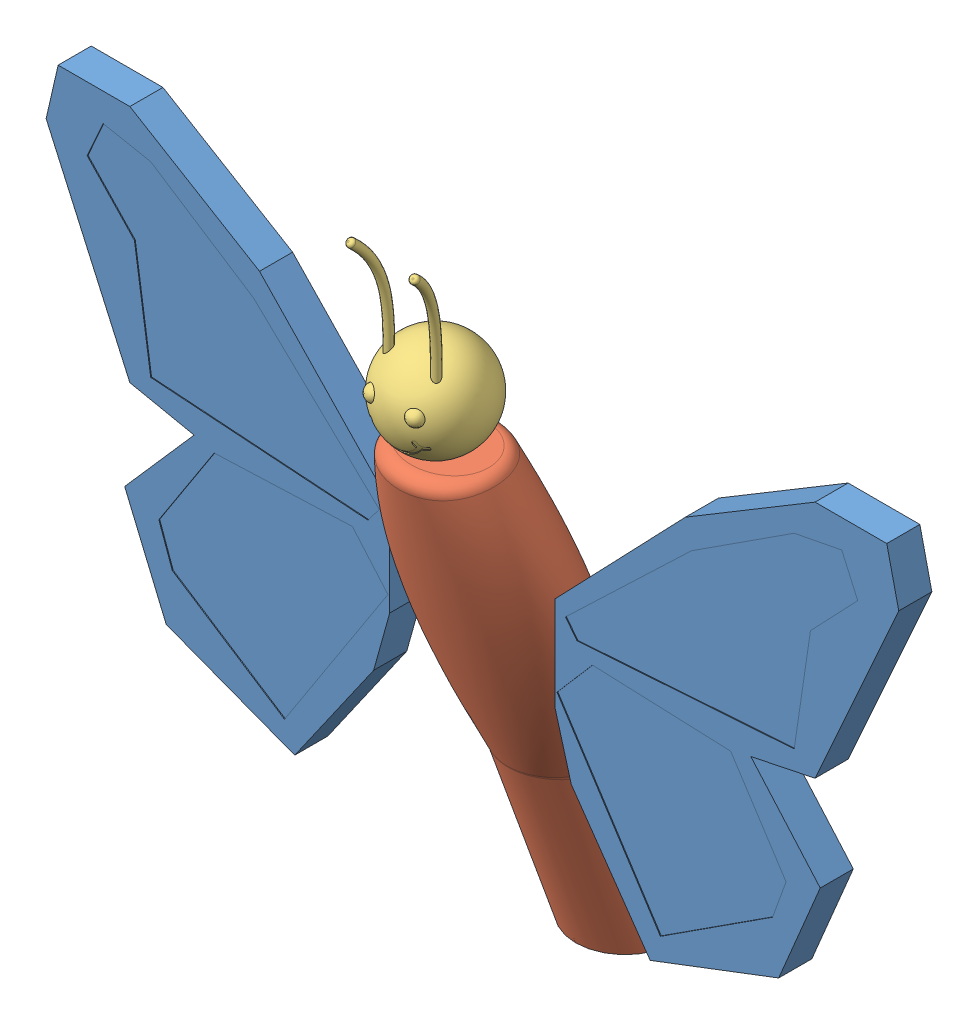
SolidWorks assembly Assem1, configuration Default. Lengths in mm.
Overall size (2617.43 2113.87 901.92).
4 component instances, 3 part files, 6 mates.
Components (placement in the parent):
- Wing-1: Wing [Default] at (371.665 221.4807 1594.4083) size (1207.07 1471.46 101.61)
- Body-1: Body [Default] at (625.7054 -140.7403 1226.9822) size (574.9 1524 859.04)
- Wing-2: Wing [Default] at (879.7459 221.4807 1696.0083) x (-1 0 0) z (0 0 -1) size (1207.07 1471.46 101.61)
- Head-1: Head [Default] at (619.7065 1535.6597 1803.3329) size (304.8 589.87 325.57)
Mates (geometry in assembly coordinates):
- Parallel1: parallel: plane of Wing-1 through (371.665 221.4807 1696.0083) normal (1 0 0); plane of Wing-2 through (879.7459 137.2835 1594.4083) normal (-1 0 0)
- Coincident2: coincident: plane of Wing-1 through (371.665 221.4807 1693.4683) normal (0 0 1); plane of Wing-2 through (879.7459 137.2835 1693.4683) normal (0 0 1)
- Tangent1: tangent: plane of Wing-1 through (371.665 221.4807 1696.0083) normal (1 0 0); face of Body-1
- Tangent2: tangent: face of Body-1; plane of Wing-2 through (879.7459 221.4807 1594.4083) normal (-1 0 0)
- Coincident3: coincident: plane of Wing-1 through (371.665 1715.2082 1696.0083) normal (0 1 0); plane of Wing-2 through (879.7459 1715.2082 1594.4083) normal (0 1 0)
- Tangent3: tangent: plane of Body-1 through (625.7054 1383.2597 1781.6729) normal (0 1 0); sphere of Head-1
